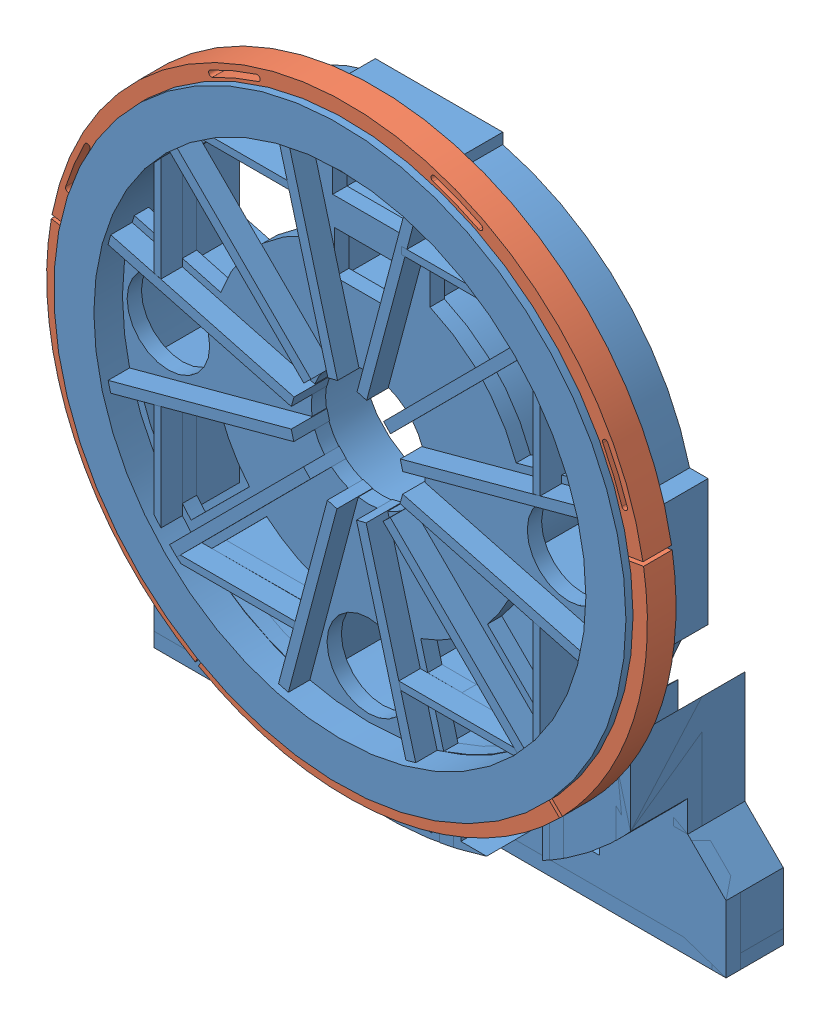
SolidWorks assembly Wheel_left_slotted_ring, configuration Default. Lengths in mm.
Overall size (542.77 462 110).
2 component instances, 2 part files, 1 mates.
Components (placement in the parent):
- wheel_left-1: wheel_left [Default] at origin size (400 452 110)
- sloted_steel_frame-1: sloted_steel_frame [Default] at (0 0 5) x (0 0 1) z (-1 0 0) size (20 420 420)
Mates (geometry in assembly coordinates):
- Coincident3: coincident: circle of wheel_left-1; circle of sloted_steel_frame-1
